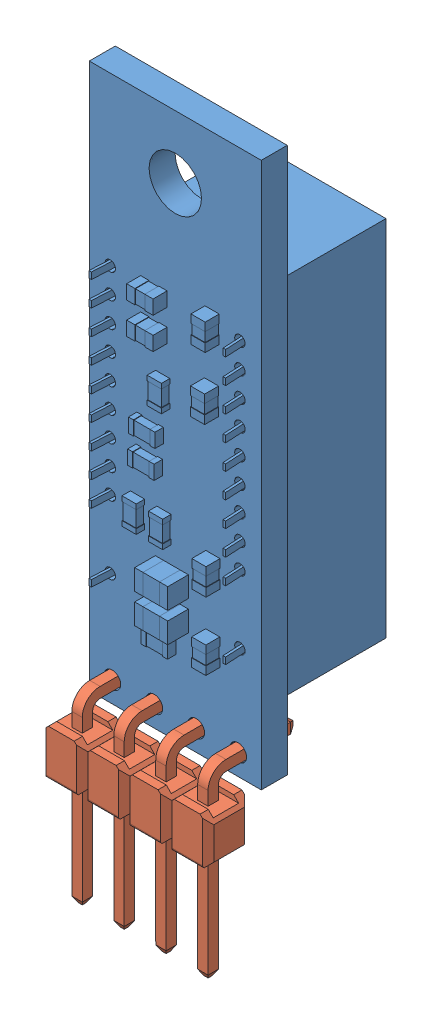
SolidWorks assembly IR_with_header, configuration Default. Lengths in mm.
Overall size (10.41 42.55 11.85).
2 component instances, 2 part files, 4 mates.
Components (placement in the parent):
- sds02a-with-sensor-1: sds02a-with-sensor [Default] at (2.0809 3.1092 30.1366) size (10.41 33.02 10.01)
- Pin Header 1x4 TH Angle Pitch 2.54mm-1: Pin Header 1x4 TH Angle Pitch 2.54mm [Default] at (3.4753 4.399 30.1366) x (0.999997 -0.0026 0) z (0 0 1) size (10.17 11.11 6.29)
Mates (geometry in assembly coordinates):
- Distance2: distance = 1.27 mm: moEndPointRef_w of Pin Header 1x4 TH Angle Pitch 2.54mm-1; plane of sds02a-with-sensor-1 through (2.0809 3.1092 28.5618) normal (0 -1 0)
- Distance3: distance = 1.4 mm: moEndPointRef_w of Pin Header 1x4 TH Angle Pitch 2.54mm-1; plane of sds02a-with-sensor-1 through (12.4949 3.1092 28.5618) normal (1 0 0)
- Coincident4: coincident anti-aligned: plane of sds02a-with-sensor-1 through (2.0809 3.1092 30.1366) normal (0 0 1); plane of Pin Header 1x4 TH Angle Pitch 2.54mm-1 through (11.4453 2.2264 30.1366) normal (0 0 -1)
- Parallel1: parallel aligned: line of sds02a-with-sensor-1 through (12.4949 36.1292 30.1366) axis (0 -1 0); line of Pin Header 1x4 TH Angle Pitch 2.54mm-1 through (12.3653 2.5892 31.032) axis (0 -1 0)
